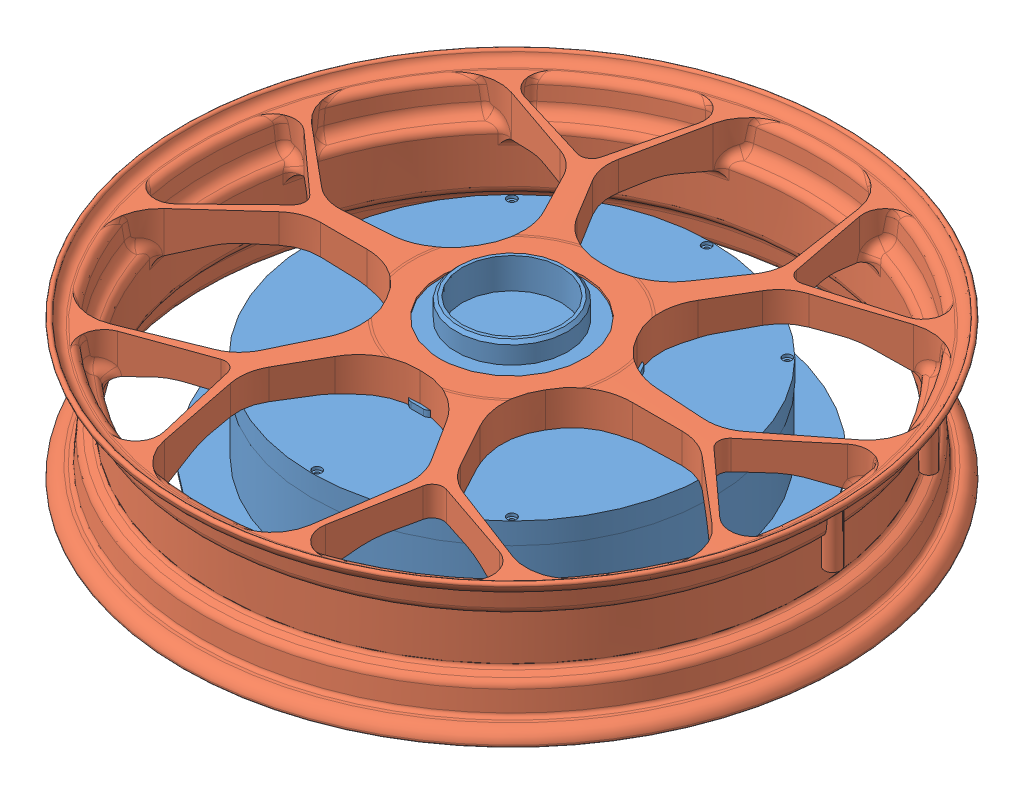
SolidWorks assembly Misubaand Disk, configuration Default. Lengths in mm.
Overall size (431.57 108 431.57).
2 component instances, 2 part files, 2 mates.
Components (placement in the parent):
- Motor Mitsuba M2096 D-III-1: Motor Mitsuba M2096 D-III [Default] at origin size (310 108 310)
- rimmachined13-1: rimmachined13 [Default] at (0 -8.3 0) x (0 1 0) z (0 0 1) size (93.59 431.57 431.57)
Mates (geometry in assembly coordinates):
- Concentric1: concentric: cylinder of Motor Mitsuba M2096 D-III-1 through (0 14 0) axis (0 -1 0) radius 47; cylinder of rimmachined13-1 through (0 0.8 0) axis (0 1 0) radius 47
- Coincident1: coincident anti-aligned: plane of Motor Mitsuba M2096 D-III-1 through (0 14 0) normal (0 1 0); plane of rimmachined13-1 through (-40 14 0) normal (0 -1 0)
